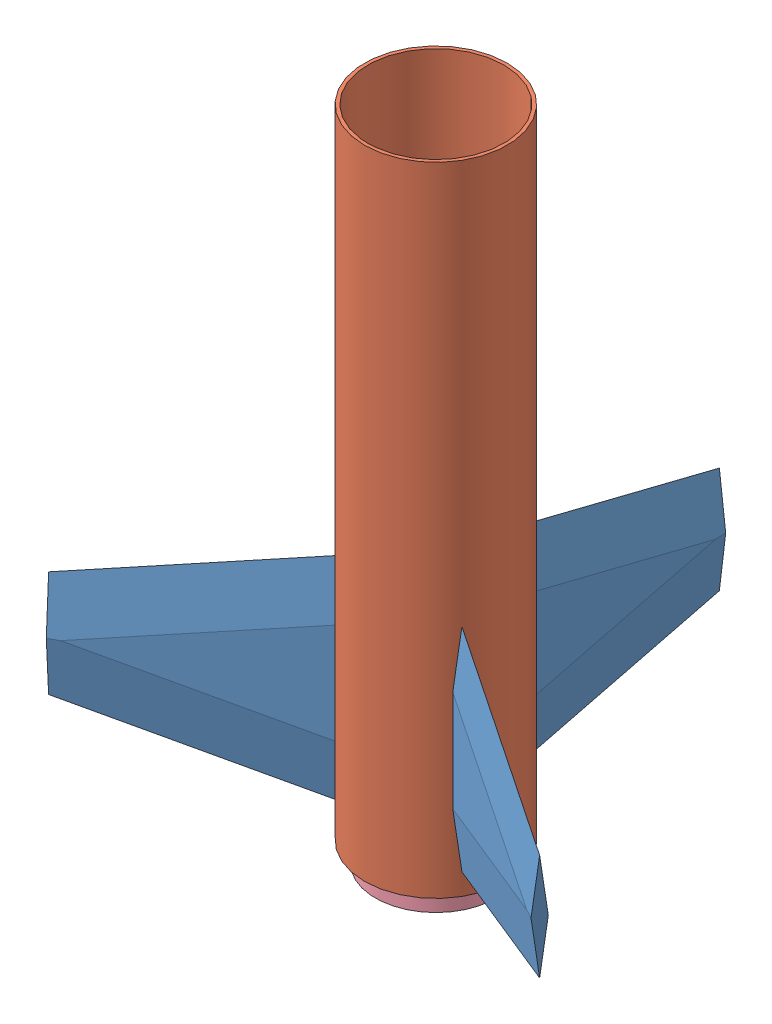
SolidWorks assembly Fin assembly, configuration Default. Lengths in mm.
Overall size (237.93 314.33 206.06).
6 component instances, 4 part files, 10 mates.
Components (placement in the parent):
- 4in to 2in taper-1: 4in to 2in taper [Default] at (-3.175 35.5473 -33.9386) size (6.35 101.57 101.6)
- bluetube 2.56in-1: bluetube 2.56in [Default] at origin size (68.17 304.8 68.17)
- 4in to 2in taper-2: 4in to 2in taper [Default] at (30.9792 35.5473 14.2197) x (-0.5 0 0.866025) z (-0.866025 0 -0.5) size (6.35 101.57 101.6)
- 4in to 2in taper-3: 4in to 2in taper [Default] at (-27.8042 35.5473 19.7189) x (-0.5 0 -0.866025) z (0.866025 0 -0.5) size (6.35 101.57 101.6)
- motor_mount-1: motor_mount [Default] at origin size (64.52 4.76 64.52)
- 54mm motor-1: 54mm motor [Default] at (0 152.4 0) x (-0.965868 0 -0.259033) z (0 1 0) size (57.79 57.79 161.93)
Mates (geometry in assembly coordinates):
- Concentric1: concentric: cylinder of ? through (0 304.8 0) axis (0 -1 0) radius 34.0868
- Coincident2: coincident anti-aligned: plane of bluetube 2.56in-1 through (0 0 0) normal (0 -1 0); plane of assembly through (0 0 0) normal (0 1 0)
- Distance1: distance = 3.175 mm aligned: plane of 4in to 2in taper-1 through (3.175 35.5473 -33.9386) normal (1 0 0); plane of assembly through (0 0 0) normal (1 0 0)
- Parallel2: parallel anti-aligned: cylinder of 4in to 2in taper-1 through (0 10.1473 0.0974) axis (0 1 0) radius 34.0868; cylinder of bluetube 2.56in-1 through (0 304.8 0) axis (0 -1 0) radius 34.0868
- Distance2: distance = 10.16 mm: plane of bluetube 2.56in-1 through (0 0 0) normal (0 -1 0); point of 4in to 2in taper-1
- Coincident5: coincident: line of 4in to 2in taper-1 through (-3.175 36.8014 -33.9386) axis (0 1 0); cylinder of bluetube 2.56in-1 through (0 304.8 0) axis (0 -1 0) radius 34.0868
- Concentric4: concentric aligned: cylinder of bluetube 2.56in-1 through (0 304.8 0) axis (0 -1 0) radius 32.512; cylinder of motor_mount-1 through (0 4.7625 0) axis (0 -1 0) radius 32.258
- Coincident6: coincident aligned: plane of bluetube 2.56in-1 through (0 0 0) normal (0 -1 0); plane of motor_mount-1 through (0 0 0) normal (0 -1 0)
- Concentric5: concentric anti-aligned: cylinder of bluetube 2.56in-1 through (0 304.8 0) axis (0 -1 0) radius 32.512; cylinder of 54mm motor-1 through (0 152.4 0) axis (0 1 0) radius 26.9875
- Coincident8: coincident anti-aligned: plane of motor_mount-1 through (0 0 0) normal (0 -1 0); plane of 54mm motor-1 through (0 0 0) normal (0 1 0)
